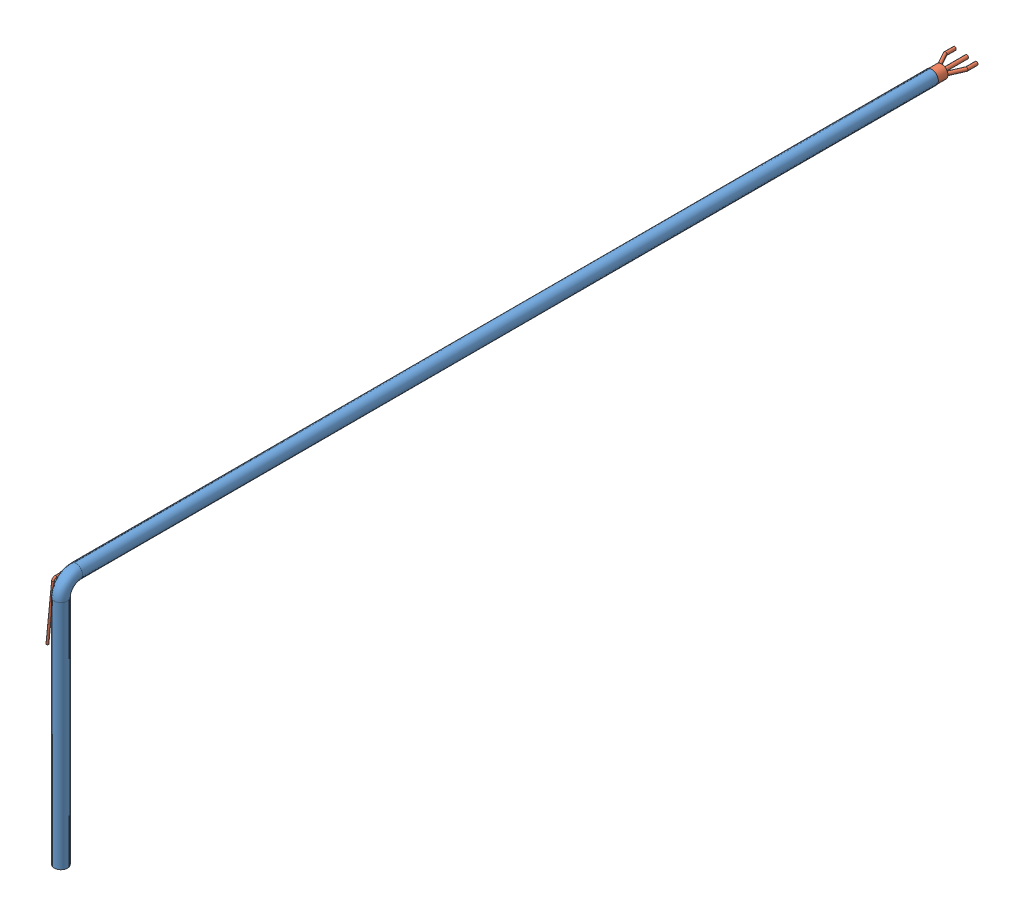
SolidWorks assembly Ensamblaje Bajada 4in, configuration Predeterminado. Lengths in mm.
Overall size (235.29 2014.23 7584.66).
2 component instances, 2 part files, 1 mates.
Components (placement in the parent):
- Bajada 4in-1: Bajada 4in [Predeterminado] at (-3685.7445 -940.5199 3026.4) x (0 1 0) z (1 0 0) size (2005.8 7306.8 122.44)
- Manga para 3 fases-1: Manga para 3 fases [Predeterminado] at (-3685.7445 -940.5199 3148.5365) x (0.995258 -0.097274 0) z (0.097274 0.995258 0) size (199.67 7185.8 375.94)
Mates (geometry in assembly coordinates):
- Concéntrica2: concentric aligned: cylinder of Bajada 4in-1 through (-3685.7445 -940.5199 3036.4) axis (0 0 1) radius 50.8; cylinder of Manga para 3 fases-1 through (-3685.7445 -940.5199 2948.5365) axis (0 0 1) radius 50.8
